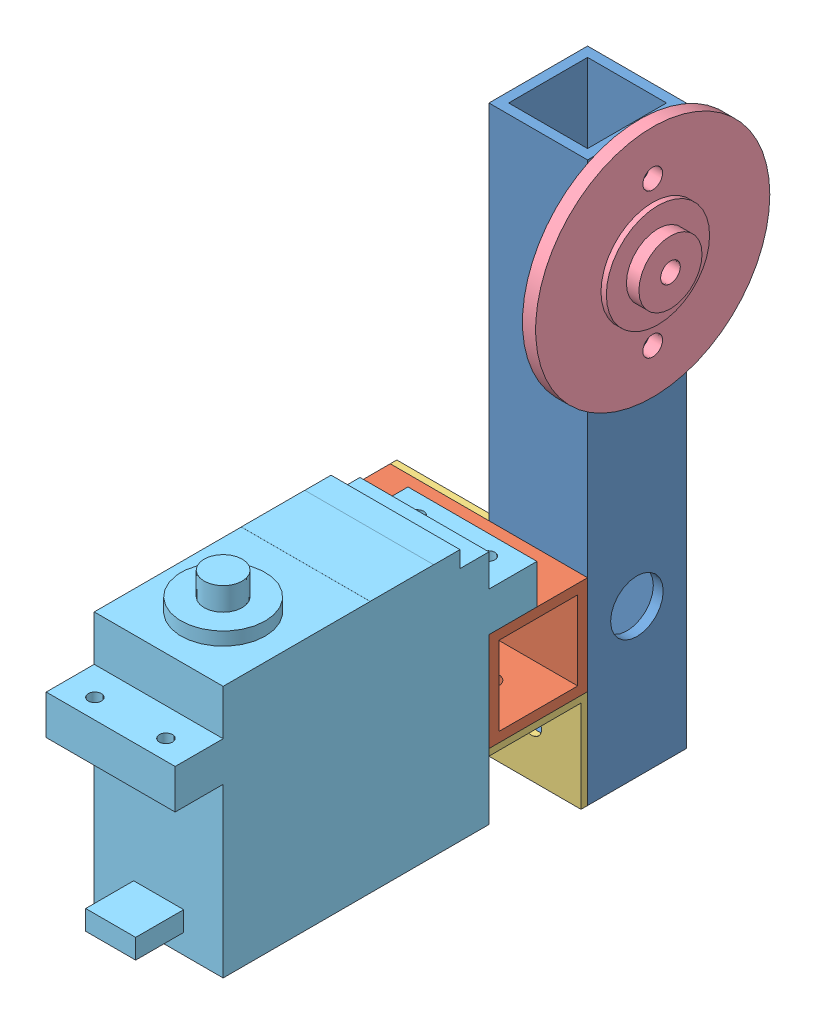
SolidWorks assembly Assem1, configuration ﾃﾞﾌｫﾙﾄ. Lengths in mm.
Overall size (35.1 86.8 88).
6 component instances, 5 part files, 9 mates.
Components (placement in the parent):
- 腕_刀_伸ばし_右腕-1: 腕_刀_伸ばし_右腕 [ﾃﾞﾌｫﾙﾄ] at (17.1394 57.9627 8.4941) x (-1 0 0) z (0 1 0) size (15 15 85)
- 腕_刀_サーボ固定_右腕-2: 腕_刀_サーボ固定_右腕 [ﾃﾞﾌｫﾙﾄ] at (-5.8505 -4.7699 23.2368) x (0 0 1) z (-1 0 0) size (15 15 30)
- 腕_刀_L字固定-1: 腕_刀_L字固定 [ﾃﾞﾌｫﾙﾄ] at (0.5028 -12.0373 10.7652) x (0 0 -1) z (0 1 0) size (15 15 15)
- 腕_刀_L字固定-2: 腕_刀_L字固定 [ﾃﾞﾌｫﾙﾄ] at (9.1495 -20.684 21.6882) x (0 0 1) z (1 0 0) size (15 15 15)
- 腕_刀_円盤-1: 腕_刀_円盤 [ﾃﾞﾌｫﾙﾄ] at (26.5495 41.9627 8.7267) x (0 0 1) z (-1 0 0) size (35.6 35.6 5.1)
- サーボ_MG995-1: サーボ_MG995 [ﾃﾞﾌｫﾙﾄ] at (40.0141 -22.0373 51.2035) x (-1 0 0) z (0 1 0) size (19.6 55 43.9)
Mates (geometry in assembly coordinates):
- 一致2: coincident aligned: circle of 腕_刀_伸ばし_右腕-1; circle of 腕_刀_L字固定-1
- 一致3: coincident aligned: circle of 腕_刀_サーボ固定_右腕-2; circle of 腕_刀_L字固定-1
- 一致4: coincident aligned: circle of 腕_刀_サーボ固定_右腕-2; circle of 腕_刀_L字固定-2
- 一致5: coincident aligned: circle of 腕_刀_伸ばし_右腕-1; circle of 腕_刀_L字固定-2
- 一致6: coincident anti-aligned: circle of 腕_刀_サーボ固定_右腕-2; circle of サーボ_MG995-1
- 一致7: coincident anti-aligned: circle of 腕_刀_サーボ固定_右腕-2; circle of サーボ_MG995-1
- 一致8: coincident: plane of 腕_刀_伸ばし_右腕-1 through (24.1495 -27.0373 16.2267) normal (1 0 0); plane of 腕_刀_円盤-1 through (24.1495 41.9627 8.7267) normal (-1 0 0)
- 同心円1: concentric: circle of 腕_刀_伸ばし_右腕-1; circle of 腕_刀_円盤-1
- 同心円2: concentric aligned: circle of 腕_刀_伸ばし_右腕-1; circle of 腕_刀_円盤-1
